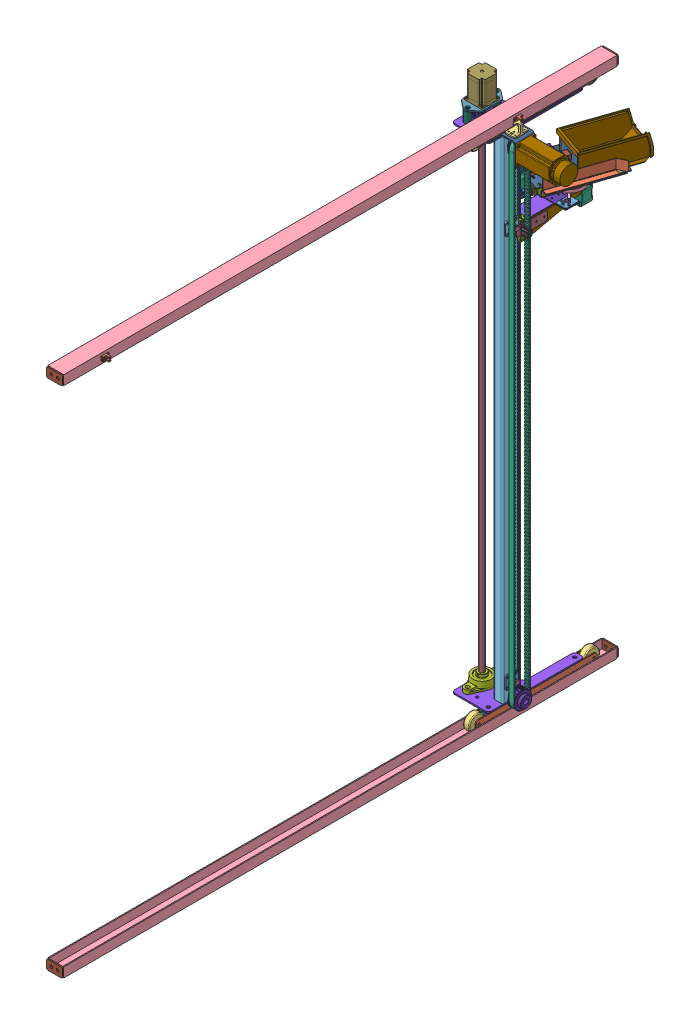
SolidWorks assembly T00001-000-R00, configuration Default. Lengths in mm.
Overall size (309.17 1703.5 1800.33).
110 component instances, 57 part files, 187 mates.
Components (placement in the parent):
- T00118-000-R00-1: T00118-000-R00 [Default] at (157.9488 226.0018 -468.4792) size (25 25 300)
- T00119-DXF-R00-1: T00119-DXF-R00 [Default] at (145.4488 226.0018 -318.4792) x (0 0 1) z (0 -1 0) size (380 3 25)
- T00119-DXF-R00-2: T00119-DXF-R00 [Default] at (173.4488 226.0018 -318.4792) x (0 0 -1) z (0 1 0) size (380 3 25)
- T00103-E00-R00-1: T00103-E00-R00 [Default] at (157.9488 226.0018 -138.4792) x (0 -0.996374 0.085085) z (0 0.085085 0.996374) size (50 22 50)
- T00103-E00-R00-2: T00103-E00-R00 [Default] at (157.9488 226.0018 -498.4792) x (0 -1 0) z (0 0 1) size (50 22 50)
- T00117-000-R00-1: T00117-000-R00 [Default] at (157.9488 198.0018 -560.9511) size (50 30 1732)
- T00112-000-R00-1: T00112-000-R00 [50 x 30 x 2.6x1700] at (142.9488 1012.5018 -263.4792) x (1 0 0) z (0 -1 0) size (30 50 1540)
- T00109-E00-R00-1: T00109-E00-R00 [HGR15R400CE20] at (157.9488 1772.5018 -263.4792) x (1 0 0) z (0 1 0) size (15 15 1530)
- T00100-E00-R00-4: T00100-E00-R00 [Default] at (82.9488 242.5018 -238.4792) x (0 1 0) z (0 0 1) size (65.14 65.88 113)
- T00120-DXF-R00-1: T00120-DXF-R00 [Default] at (100.4488 238.5018 -238.4792) x (0 0 -1) z (-1 0 0) size (300 4 115)
- T00120-DXF-R00-2: T00120-DXF-R00 [Default] at (100.4488 1782.5018 -238.4792) x (0 0 -1) z (-1 0 0) size (300 4 115)
- T00100-E00-R00-2: T00100-E00-R00 [Default] at (82.9488 1782.5018 -238.4792) x (0 -1 0) z (0 0 -1) size (65.14 65.88 113)
- T00160-E00-R00-8: T00160-E00-R00 [Default] at (216.9488 1755.5018 -238.4792) x (0 0 1) z (-1 0 0) size (60 69 159.8)
- T00121-0A4-R00-1: T00121-0A4-R00 [Default] at (216.9488 1751.5018 -238.4792) x (0 0 -1) z (0 -1 0) size (300 74 94)
- T00103-E00-R00-3: T00103-E00-R00 [Default] at (157.9488 1803.0018 -138.4792) x (0 -1 0) z (0 0 1) size (50 22 50)
- T00103-E00-R00-4: T00103-E00-R00 [Default] at (157.9488 1803.0018 -498.4792) x (0 0.952135 0.305677) z (0 0.305677 -0.952135) size (50 22 50)
- T00119-DXF-R00-3: T00119-DXF-R00 [Default] at (173.4488 1803.0018 -318.4792) x (0 0 1) z (0 -1 0) size (380 3 25)
- T00119-DXF-R00-4: T00119-DXF-R00 [Default] at (145.4488 1803.0018 -318.4792) x (0 0 -1) z (0 1 0) size (380 3 25)
- T00118-000-R00-2: T00118-000-R00 [Default] at (157.9488 1803.0018 -168.4792) x (1 0 0) z (0 0 -1) size (25 25 300)
- T00117-000-R00-2: T00117-000-R00 [Default] at (157.9488 1833.5018 -560.9511) x (-1 0 0) z (0 0 1) size (50 30 1732)
- T00122-DXF-R00-1: T00122-DXF-R00 [Default] at (157.9488 213.0018 1175.0489) size (50 30 4)
- T00122-DXF-R00-2: T00122-DXF-R00 [Default] at (157.9488 213.0018 -560.9511) size (50 30 4)
- T00122-DXF-R00-3: T00122-DXF-R00 [Default] at (157.9488 1818.5018 -564.9511) x (-1 0 0) z (0 0 -1) size (50 30 4)
- T00122-DXF-R00-4: T00122-DXF-R00 [Default] at (157.9488 1818.5018 1175.0489) size (50 30 4)
- T00106-E00-R00-6: T00106-E00-R00 [Default] at (84.9717 1862.7018 -130.0077) x (0 0 1) z (0 -1 0) size (56.4 57 96.6)
- T00123-000-R00-1: T00123-000-R00 [Default] at (82.9488 1823.9018 -238.4792) x (1 0 0) z (0 -1 0) size (15 15 1615)
- T00124-DXF-R00-1: T00124-DXF-R00 [Default] at (82.9488 1825.5018 -238.4792) x (0 0 1) z (-1 0 0) size (110 4 65)
- T00104-E00-R00-1: T00104-E00-R00 [Default] at (82.9488 1786.5018 -193.4792) x (0 1 0) z (0 0 1) size (35 20 20)
- T00104-E00-R00-2: T00104-E00-R00 [Default] at (82.9488 1786.5018 -283.4792) x (0 1 0) z (0 0 1) size (35 20 20)
- T00101-E00-R00-1: T00101-E00-R00 [Default] at (112.9488 1791.0018 -193.4792) size (22 7 22)
- T00101-E00-R00-2: T00101-E00-R00 [Default] at (112.9488 1791.0018 -283.4792) size (22 7 22)
- T00101-E00-R00-3: T00101-E00-R00 [Default] at (112.9488 1798.0018 -283.4792) x (-0.837169 0 -0.546944) z (-0.546944 0 0.837169) size (22 7 22)
- T00101-E00-R00-4: T00101-E00-R00 [Default] at (112.9488 1798.0018 -193.4792) x (-0.837169 0 -0.546944) z (-0.546944 0 0.837169) size (22 7 22)
- T00101-E00-R00-5: T00101-E00-R00 [Default] at (112.9488 234.0018 -283.4792) size (22 7 22)
- T00101-E00-R00-6: T00101-E00-R00 [Default] at (112.9488 227.0018 -283.4792) size (22 7 22)
- T00101-E00-R00-7: T00101-E00-R00 [Default] at (112.9488 234.0018 -193.4792) x (-0.837169 0 -0.546944) z (-0.546944 0 0.837169) size (22 7 22)
- T00101-E00-R00-8: T00101-E00-R00 [Default] at (112.9488 227.0018 -193.4792) x (-0.837169 0 -0.546944) z (-0.546944 0 0.837169) size (22 7 22)
- T00102-E00-R00-1: T00102-E00-R00 [Default] at (82.9488 237.5018 -238.4792) x (0 -1 0) z (-0.546944 0 0.837169) size (31 54 54)
- T00102-E00-R00-2: T00102-E00-R00 [Default] at (82.9488 1787.5018 -238.4792) x (0 1 0) z (0 0 1) size (31 54 54)
- T00102-E00-R00-3: T00102-E00-R00 [Default] at (210.9488 1755.5018 -238.4792) x (-1 0 0) z (0 -0.919553 -0.392965) size (31 54 54)
- T00125-0A4-R00-1: T00125-0A4-R00 [Default] at (137.9488 260.2518 -238.4792) x (0 0.966097 0.25818) z (0 0.25818 -0.966097) size (15 71.4 15)
- T00102-E00-R00-5: T00102-E00-R00 [Default] at (189.9488 260.2518 -238.4792) x (1 0 0) z (0 0.556413 0.830906) size (31 54 54)
- T00152-03D-R00-4: T00152-03D-R00 [Default] at (172.9488 297.5018 -238.6792) x (0 -1 0) z (0 0 1) size (40 4 40)
- T00149-E00-R00-2: T00149-E00-R00 [Default] at (195.8488 1815.5018 -247.7511) x (0 0 1) z (0 1 0) size (22.7 14.9 13.4)
- T00149-E00-R00-3: T00149-E00-R00 [Default] at (195.8488 1821.5018 1041.6323) x (0 0 -1) z (0 -1 0) size (22.7 14.9 13.4)
- T00150-03D-R00-3: T00150-03D-R00 [Default] at (191.1488 1790.5018 -238.4792) x (0 0 -1) z (1 0 0) size (45 29.75 32)
- T00153-E00-R00-1: T00153-E00-R00 [Default] at (180.9488 1523.996 -247.6792) x (0 -1 0) z (1 0 0) size (13 22.4 13.7)
- T00151-03D-R00-1: T00151-03D-R00 [Default] at (172.9488 1527.496 -238.4792) x (0 -1 0) z (0 0 1) size (40 4 40)
- T00153-E00-R00-2: T00153-E00-R00 [Default] at (180.9488 294.0018 -247.4815) x (0 -1 0) z (1 0 0) size (13 22.4 13.7)
- T00166-E00-R00-1: T00166-E00-R00 [Default] at (193.6988 1755.5018 107.1126) x (0 0 -1) z (1 0 0) size (52.05 1547.3 15)
- T00003-000-R02-2: T00003-000-R02 [Default] at (0 635.6909 -533.1535) size (206.44 185.95 380.78)
  - T00108-E00-R00-3: T00108-E00-R00 [Default] at (157.9488 862.2474 269.7743) x (1 0 0) z (0 1 0) size (34 23.7 61.49)
  - T00110-E00-R00-1: T00110-E00-R00 [HGR15R400CE20] at (220.7447 918.7474 -18.1171) x (-0.945846 0 -0.324616) z (0.324616 0 -0.945846) size (15 15 270)
  - T00108-E00-R00-4: T00108-E00-R00 [Default] at (154.4543 918.7474 175.0355) x (-0.945846 0 -0.324616) z (0.324616 0 -0.945846) size (34 23.7 61.49)
  - T00148-E00-R00-1: T00148-E00-R00 [Default] at (206.0289 941.2474 119.0644) x (-0.945846 0 -0.324616) z (0.324616 0 -0.945846) size (104.77 76.2 187.32)
  - T00006-000-R00-1: T00006-000-R00 [Default] at (104.8241 969.1581 159.4141) x (-0.945846 0 -0.324616) z (0 -1 0) size (100 103 92)
    - T00126-000-R02-1: T00126-000-R02 [Default] at (-76.7384 90.3354 70.4106) size (82 103 92)
    - T00005-000-R00-1: T00005-000-R00 [Default] at (-79.4687 62.4093 14.8739) x (0 -1 0) z (1 0 0) size (53.8 27.95 21.5)
      - T00154-E00-R01-1: T00154-E00-R01 [Default] at (15.674 22.2087 43.7303) size (53.8 16.25 21.5)
      - T00172-000-R01-1: T00172-000-R01 [Default] at (22.774 33.8087 43.7303) size (39 12 21.5)
      - T00171-000-R01-1: T00171-000-R01 [Default] at (15.674 10.2087 43.7303) size (53.2 12 21.5)
      - T00173-000-R01-1: T00173-000-R01 [Default] at (25.474 28.1587 43.0803) size (6 10 6)
      - socket head cap screw_iso-1: socket head cap screw_iso [ISO 4762 M2 x 16 - 16C] at (40.074 37.8087 51.9803) x (0 -1 0) z (0 0 1) size (18 3.8 3.8)
      - socket head cap screw_iso-4: socket head cap screw_iso [ISO 4762 M2 x 16 - 16C] at (5.074 37.8087 51.9803) x (0 -1 0) z (0 0 1) size (18 3.8 3.8)
      - socket head cap screw_iso-5: socket head cap screw_iso [ISO 4762 M2 x 16 - 16C] at (40.074 37.8087 35.4803) x (0 -1 0) z (0 0 1) size (18 3.8 3.8)
    - socket head cap screw_iso-1: socket head cap screw_iso [ISO 4762 M3 x 16 - 16C] at (-35.7384 58.3354 -6.3347) x (0 0 1) z (0 -1 0) size (19 5.5 5.5)
    - socket head cap screw_iso-2: socket head cap screw_iso [ISO 4762 M3 x 16 - 16C] at (-35.7384 35.3354 -6.3347) x (0 0 1) z (0 -1 0) size (19 5.5 5.5)
    - hex thin nut chamfered gradeab_iso-1: hex thin nut chamfered gradeab_iso [ISO - 4035 - M3 - C] at (-35.7384 35.3354 8.4653) size (5.5 6.35 1.8)
    - hex thin nut chamfered gradeab_iso-2: hex thin nut chamfered gradeab_iso [ISO - 4035 - M3 - C] at (-35.7384 58.3354 8.4653) size (5.5 6.35 1.8)
    - T00163-03D-R01-1: T00163-03D-R01 [Default] at (-4.7384 50.3354 4.6653) x (1 0 0) z (0 0 -1) size (38 30 18.2)
    - socket countersunk head screw_iso-1: socket countersunk head screw_iso [ISO 10642 - M3 x 8 - 8C] at (-9.7384 59.3354 1.6553) x (0 0 1) z (0.923728 0.383049 0) size (8 5.54 5.54)
    - socket countersunk head screw_iso-2: socket countersunk head screw_iso [ISO 10642 - M3 x 8 - 8C] at (-9.7384 41.3354 1.6553) x (0 0 1) z (0.923728 0.383049 0) size (8 5.54 5.54)
    - hex thin nut chamfered gradeab_iso-5: hex thin nut chamfered gradeab_iso [ISO - 4035 - M3 - C] at (-9.7384 41.3354 8.4653) size (5.5 6.35 1.8)
    - hex thin nut chamfered gradeab_iso-6: hex thin nut chamfered gradeab_iso [ISO - 4035 - M3 - C] at (-9.7384 59.3354 8.4653) size (5.5 6.35 1.8)
  - T00127-E00-R00-1: T00127-E00-R00 [DIN 625 - 6002 - 12,SI,NC,12_68] at (157.9488 901.2474 97.7743) x (0 1 0) z (0 0 1) size (9 32 32)
  - T00128-0A4-R00-1: T00128-0A4-R00 [Default] at (157.9488 887.7474 97.7743) x (1 0 0) z (0 -1 0) size (25 25 21)
  - T00129-E00-R00-1: T00129-E00-R00 [Circlip DIN 471 - 15 x 1.5] at (157.9488 905.9474 97.7743) x (0.837169 0 0.546944) z (0 -1 0) size (17.74 21.49 1.5)
  - T00130-0A4-R01-1: T00130-0A4-R01 [Default] at (157.9488 895.7474 97.7743) x (0.324616 0 -0.945846) z (0 -1 0) size (90 90 20)
  - T00132-E00-R00-4: T00132-E00-R00 [Metric - Spur gear 1M 60T 20PA 9FW ---S60N75H50L42N] at (157.9488 896.7474 97.7743) x (0 1 0) z (0 0 1) size (9 61.95 61.95)
  - T00107-E00-R00-1: T00107-E00-R00 [Varsayılan] at (157.9488 879.7474 61.7743) x (-1 0 0) z (0 1 0) size (42 58.5 65.65)
  - T00131-E00-R00-2: T00131-E00-R00 [Metric - Spur gear 1M 12T 20PA 8FW ---S12O10H14L5N] at (157.9488 896.7474 61.7743) x (0 1 0) z (0.924225 0 0.381849) size (14 13.61 13.61)
  - T00133-0A4-R00-3: T00133-0A4-R00 [Default] at (157.9488 862.2474 237.7743) x (1 0 0) z (0 1 0) size (49 210 57)
  - T00134-DXF-R00-1: T00134-DXF-R00 [Default] at (130.4488 892.7474 239.7743) x (0 0 -1) z (-1 0 0) size (155 44.25 3)
  - T00134-DXF-R00-2: T00134-DXF-R00 [Default] at (182.4488 892.7474 239.7743) x (0 0 -1) z (-1 0 0) size (155 44.25 3)
  - T00105-E00-R00-1: T00105-E00-R00 [Default] at (142.4488 890.7474 46.2743) x (1 0 0) z (0 -1 0) size (6 6 11)
  - T00105-E00-R00-2: T00105-E00-R00 [Default] at (173.4488 890.7474 46.2743) x (0.974973 0 -0.222324) z (0 -1 0) size (6 6 11)
  - T00105-E00-R00-3: T00105-E00-R00 [Default] at (142.4488 890.7474 77.2743) x (1 0 0) z (0 -1 0) size (6 6 11)
  - T00105-E00-R00-4: T00105-E00-R00 [Default] at (173.4488 890.7474 77.2743) x (1 0 0) z (0 -1 0) size (6 6 11)
  - T00107-E00-R00-2: T00107-E00-R00 [Varsayılan] at (104.3679 933.2474 184.5821) x (0.945846 0 0.324616) z (0.324616 0 -0.945846) size (42 58.5 65.65)
  - T00111-E00-R00-1: T00111-E00-R00 [Default] at (182.9251 933.2474 -44.3126) x (-0.536568 -0.823519 -0.184151) z (-0.778922 0.567289 -0.267328) size (10 240 10)
  - T00135-DXF-R01-1: T00135-DXF-R01 [Default] at (162.818 918.7474 83.5866) x (-0.324616 0 0.945846) z (-0.945846 0 -0.324616) size (219 39 131)
  - T00136-DXF-R01-1: T00136-DXF-R01 [Default] at (187.4488 877.7474 233.7743) x (0 0 -1) z (1 0 0) size (94.88 30 25)
  - T00138-000-R00-1: T00138-000-R00 [gespiegeld] at (139.5613 941.2474 -4.2179) x (0.324616 0 -0.945846) z (0.945846 0 0.324616) size (201.93 32 21.92)
  - T00153-E00-R00-4: T00153-E00-R00 [Default] at (89.0052 977.2474 133.8476) x (-0.324616 0 0.945846) z (0 1 0) size (13 22.4 13.7)
  - socket head cap screw_iso-1: socket head cap screw_iso [ISO 4762 M3 x 16 - 16N] at (76.144 978.7474 122.0328) x (0 -1 0) z (0.992143 0 0.125105) size (19 5.5 5.5)
  - hex nut style 1 gradeab_iso-1: hex nut style 1 gradeab_iso [ISO - 4032 - M3 - W - N] at (76.144 965.2474 122.0328) x (0.998096 0 0.061684) z (0 1 0) size (5.5 6.35 2.4)
  - socket head cap screw_iso-2: socket head cap screw_iso [ISO 4762 M3 x 16 - 16N] at (82.7649 978.7474 124.3052) x (0 -1 0) z (-0.061684 0 0.998096) size (19 5.5 5.5)
  - socket head cap screw_iso-3: socket head cap screw_iso [ISO 4762 M3 x 8 - 8N] at (86.5483 949.2474 125.6036) x (0.945846 0 0.324616) z (-0.316094 -0.227635 0.921014) size (11 5.5 5.5)
  - socket head cap screw_iso-4: socket head cap screw_iso [ISO 4762 M3 x 8 - 8N] at (86.5483 957.2474 125.6036) x (0.945846 0 0.324616) z (-0.159414 -0.871112 0.46449) size (11 5.5 5.5)
  - hex nut style 1 gradeab_iso-3: hex nut style 1 gradeab_iso [ISO - 4032 - M3 - W - N] at (82.7649 965.5626 124.3052) x (0.95019 0 0.311672) z (0 1 0) size (5.5 6.35 2.4)
  - hex nut style 1 gradeab_iso-4: hex nut style 1 gradeab_iso [ISO - 4032 - M3 - W - N] at (94.115 957.2474 128.2005) x (0.159414 0.871112 -0.46449) z (-0.945846 0 -0.324616) size (5.5 6.35 2.4)
  - hex nut style 1 gradeab_iso-5: hex nut style 1 gradeab_iso [ISO - 4032 - M3 - W - N] at (94.115 949.2474 128.2005) x (0.159414 0.871112 -0.46449) z (-0.945846 0 -0.324616) size (5.5 6.35 2.4)
  - T00153-E00-R00-7: T00153-E00-R00 [Default] at (120.7549 900.9974 134.9681) x (0.707107 0 0.707107) z (0 1 0) size (13 22.4 13.7)
  - T00153-E00-R00-8: T00153-E00-R00 [Default] at (195.1426 900.9974 134.9681) x (0.707107 0 -0.707107) z (0 1 0) size (13 22.4 13.7)
  - T00168-03D-R00-2: T00168-03D-R00 [Default] at (93.1692 959.2474 127.8759) x (-0.324616 0 0.945846) z (-0.945846 0 -0.324616) size (20 28 25.65)
  - T00161-0A4-R00-2: T00161-0A4-R00 [Default] at (157.9488 894.7474 147.7835) size (125 2 45)
  - T00164-03D-R00-1: T00164-03D-R00 [Default] at (157.9488 896.7474 147.7835) x (1 0 0) z (0 1 0) size (32 42.2 3)
  - T00165-03D-R00-1: T00165-03D-R00 [Default] at (250.9488 896.7474 147.7835) x (1 0 0) z (0 1 0) size (32 42.2 3)
  - T00137-000-R00-2: T00137-000-R00 [gespiegeld] at (236.0376 941.2474 28.893) x (0.324616 0 -0.945846) z (0.945846 0 0.324616) size (201.93 32 21.92)
  - T00162-03D-R03-1: T00162-03D-R03 [Default] at (174.1796 915.7474 50.482) x (-0.945846 0 -0.324616) z (0 -1 0) size (28 24.69 9)
Mates (geometry in assembly coordinates):
- Coincident1: coincident: plane of T00118-000-R00-1 through (170.4488 216.5018 -168.4792) normal (1 0 0); plane of T00119-DXF-R00-2 through (170.4488 228.5018 -498.4792) normal (-1 0 0)
- Coincident2: coincident: plane of T00118-000-R00-1 through (148.4488 238.5018 -168.4792) normal (0 1 0); plane of T00119-DXF-R00-2 through (170.4488 238.5018 -138.4792) normal (0 1 0)
- Coincident3: coincident: plane of T00118-000-R00-1 through (145.4488 216.5018 -168.4792) normal (-1 0 0); plane of T00119-DXF-R00-1 through (145.4488 223.5018 -138.4792) normal (1 0 0)
- Coincident4: coincident: plane of T00118-000-R00-1 through (148.4488 213.5018 -168.4792) normal (0 -1 0); plane of T00119-DXF-R00-1 through (142.4488 213.5018 -498.4792) normal (0 -1 0)
- Coincident5: coincident: plane of T00119-DXF-R00-1 through (142.4488 228.5018 -128.4792) normal (0 0 1); plane of T00119-DXF-R00-2 through (170.4488 223.5018 -128.4792) normal (0 0 1)
- Width1: width: plane of T00119-DXF-R00-1 through (142.4488 228.5018 -128.4792) normal (0 0 1); plane of T00119-DXF-R00-1 through (142.4488 228.5018 -508.4792) normal (0 0 -1); plane of T00118-000-R00-1 through (148.4488 216.5018 -468.4792) normal (0 0 -1); plane of T00118-000-R00-1 through (148.4488 216.5018 -168.4792) normal (0 0 1)
- Concentric1: concentric: cylinder of T00119-DXF-R00-1 through (142.4488 226.0018 -138.4792) axis (1 0 0) radius 3.25; cylinder of T00103-E00-R00-1 through (157.9488 226.0018 -138.4792) axis (-1 0 0) radius 3
- Concentric2: concentric: cylinder of T00119-DXF-R00-1 through (142.4488 226.0018 -498.4792) axis (1 0 0) radius 3.25; cylinder of T00103-E00-R00-2 through (157.9488 226.0018 -498.4792) axis (-1 0 0) radius 3
- Width2: width: plane of T00103-E00-R00-2 through (168.9488 223.0018 -498.4792) normal (1 0 0); plane of T00103-E00-R00-2 through (146.9488 219.0018 -498.4792) normal (-1 0 0); plane of T00119-DXF-R00-1 through (145.4488 223.5018 -138.4792) normal (1 0 0); plane of T00119-DXF-R00-2 through (170.4488 228.5018 -498.4792) normal (-1 0 0)
- Width3: width: plane of T00103-E00-R00-1 through (168.9488 223.0127 -138.2239) normal (1 0 0); plane of T00103-E00-R00-1 through (146.9488 219.0272 -137.8836) normal (-1 0 0); plane of T00119-DXF-R00-1 through (142.4488 223.5018 -138.4792) normal (-1 0 0); plane of T00119-DXF-R00-2 through (173.4488 228.5018 -498.4792) normal (1 0 0)
- Tangent1: tangent: cylinder of T00103-E00-R00-1 through (157.9488 226.0018 -138.4792) axis (-1 0 0) radius 25; plane of T00117-000-R00-1 through (135.9488 201.0018 1171.0489) normal (0 1 0)
- Tangent2: tangent: cylinder of T00103-E00-R00-2 through (157.9488 226.0018 -498.4792) axis (-1 0 0) radius 25; plane of T00117-000-R00-1 through (135.9488 201.0018 1171.0489) normal (0 1 0)
- Width4: width: plane of T00119-DXF-R00-2 through (173.4488 228.5018 -498.4792) normal (1 0 0); plane of T00119-DXF-R00-1 through (142.4488 223.5018 -138.4792) normal (-1 0 0); plane of T00117-000-R00-1 through (179.9488 201.0018 1171.0489) normal (-1 0 0); plane of T00117-000-R00-1 through (135.9488 201.0018 1171.0489) normal (1 0 0)
- Width9: width: plane of T00112-000-R00-1 through (172.9488 242.5018 -218.6792) normal (1 0 0); plane of T00112-000-R00-1 through (142.9488 242.5018 -258.2792) normal (-1 0 0); plane of T00119-DXF-R00-1 through (142.4488 223.5018 -138.4792) normal (-1 0 0); plane of T00119-DXF-R00-2 through (173.4488 228.5018 -498.4792) normal (1 0 0)
- Coincident16: coincident: plane of T00112-000-R00-1 through (148.1488 242.5018 -263.4792) normal (0 0 -1); plane of T00109-E00-R00-1 through (150.9488 242.5018 -263.4792) normal (0 0 1)
- Width10: width: plane of T00003-000-R02-2/T00108-E00-R00-3 through (162.6988 1527.1383 -269.7949) normal (-1 0 0); plane of T00003-000-R02-2/T00108-E00-R00-3 through (153.1988 1527.1383 -269.7949) normal (1 0 0); plane of T00109-E00-R00-1 through (150.4488 242.5018 -275.1449) normal (-1 0 0); plane of T00109-E00-R00-1 through (165.4488 242.5018 -275.1449) normal (1 0 0)
- Coincident18: coincident: plane of T00003-000-R02-2/T00108-E00-R00-3 through (162.9902 1517.6383 -278.4792) normal (0 0 1); plane of T00109-E00-R00-1 through (162.9488 242.5018 -278.4792) normal (0 0 -1)
- Width11: width: plane of T00112-000-R00-1 through (172.9488 242.5018 -218.6792) normal (1 0 0); plane of T00112-000-R00-1 through (142.9488 242.5018 -258.2792) normal (-1 0 0); plane of T00109-E00-R00-1 through (150.4488 242.5018 -263.9792) normal (-1 0 0); plane of T00109-E00-R00-1 through (165.4488 242.5018 -263.9792) normal (1 0 0)
- Coincident62: coincident: plane of T00118-000-R00-1 through (148.4488 238.5018 -168.4792) normal (0 1 0); plane of T00120-DXF-R00-1 through (100.4488 238.5018 -238.4792) normal (0 -1 0)
- Width15: width: plane of T00120-DXF-R00-1 through (142.9488 242.5018 -308.4792) normal (-1 0 0); plane of T00120-DXF-R00-1 through (172.9488 242.5018 -168.4792) normal (1 0 0); plane of T00119-DXF-R00-1 through (142.4488 223.5018 -138.4792) normal (-1 0 0); plane of T00119-DXF-R00-2 through (173.4488 228.5018 -498.4792) normal (1 0 0)
- Coincident63: coincident: plane of T00118-000-R00-1 through (148.4488 216.5018 -168.4792) normal (0 0 1); plane of T00120-DXF-R00-1 through (57.9488 242.5018 -168.4792) normal (0 0 1)
- Width16: width: plane of T00120-DXF-R00-1 through (57.9488 242.5018 -168.4792) normal (0 0 1); plane of T00120-DXF-R00-1 through (57.9488 242.5018 -308.4792) normal (0 0 -1); plane of T00112-000-R00-1 through (148.1488 242.5018 -263.4792) normal (0 0 -1); plane of T00112-000-R00-1 through (167.7488 242.5018 -213.4792) normal (0 0 1)
- Coincident64: coincident: plane of T00109-E00-R00-1 through (164.4488 242.5018 -266.565) normal (0 -1 0); plane of T00120-DXF-R00-1 through (100.4488 242.5018 -238.4792) normal (0 1 0)
- Coincident65: coincident: plane of T00112-000-R00-1 through (167.7488 242.5018 -218.6792) normal (0 -1 0); plane of T00120-DXF-R00-1 through (100.4488 242.5018 -238.4792) normal (0 1 0)
- Coincident70: coincident: plane of T00100-E00-R00-4 through (82.9488 242.5018 -238.4792) normal (0 -1 0); plane of T00120-DXF-R00-1 through (100.4488 242.5018 -238.4792) normal (0 1 0)
- Concentric28: concentric: cylinder of T00120-DXF-R00-1 through (82.9488 242.5018 -193.4792) axis (0 -1 0) radius 6.25; cylinder of T00100-E00-R00-4 through (82.9488 248.5018 -193.4792) axis (0 1 0) radius 6
- Concentric29: concentric: cylinder of T00120-DXF-R00-1 through (82.9488 242.5018 -283.4792) axis (0 -1 0) radius 6.25; circle of T00100-E00-R00-4
- Coincident78: coincident: plane of T00112-000-R00-1 through (167.7488 1782.5018 -218.6792) normal (0 1 0); plane of T00120-DXF-R00-2 through (100.4488 1782.5018 -238.4792) normal (0 -1 0)
- Coincident79: coincident: plane of T00120-DXF-R00-1 through (57.9488 242.5018 -168.4792) normal (0 0 1); plane of T00120-DXF-R00-2 through (57.9488 1786.5018 -168.4792) normal (0 0 1)
- Coincident80: coincident: plane of T00120-DXF-R00-1 through (57.9488 242.5018 -308.4792) normal (-1 0 0); plane of T00120-DXF-R00-2 through (57.9488 1786.5018 -308.4792) normal (-1 0 0)
- Coincident81: coincident: plane of T00120-DXF-R00-2 through (100.4488 1782.5018 -28.555) normal (0 -1 0); plane of ? through (82.9488 1782.5018 -28.555) normal (0 1 0)
- Concentric32: concentric: cylinder of T00120-DXF-R00-2 through (82.9488 1786.5018 -73.555) axis (0 -1 0) radius 6.25; cylinder of ? through (82.9488 1776.5018 -73.555) axis (0 -1 0) radius 6
- Concentric33: concentric: cylinder of T00120-DXF-R00-2 through (82.9488 1786.5018 16.445) axis (0 -1 0) radius 6.25; cylinder of ? through (82.9488 1776.5018 16.445) axis (0 -1 0) radius 6
- Coincident86: coincident: plane of T00120-DXF-R00-2 through (100.4488 1786.5018 -238.4792) normal (0 1 0); plane of T00121-0A4-R00-1 through (216.9488 1786.5018 -238.4792) normal (0 -1 0)
- Concentric37: concentric: cylinder of T00120-DXF-R00-2 through (157.9488 1786.5018 -183.4792) axis (0 -1 0) radius 5.25; cylinder of T00121-0A4-R00-1 through (157.9488 1786.5018 -183.4792) axis (0 1 0) radius 5.25
- Concentric38: concentric: cylinder of T00120-DXF-R00-2 through (157.9488 1786.5018 -453.4792) axis (0 -1 0) radius 5.25; cylinder of T00121-0A4-R00-1 through (157.9488 1786.5018 -453.4792) axis (0 1 0) radius 5.25
- Coincident87: coincident: plane of T00160-E00-R00-8 through (216.9488 1728.5018 -265.4792) normal (-1 0 0); plane of T00121-0A4-R00-1 through (216.9488 1711.5018 -255.9792) normal (1 0 0)
- LimitDistance3: limit distance = 1299.5281 mm: plane of T00119-DXF-R00-2 through (170.4488 223.5018 -128.4792) normal (0 0 1); plane of T00117-000-R00-1 through (157.9488 198.0018 1171.0489) normal (0 0 1)
- Coincident93: coincident: plane of T00119-DXF-R00-3 through (170.4488 1790.5018 -498.4792) normal (0 -1 0); plane of T00118-000-R00-2 through (148.4488 1790.5018 -468.4792) normal (0 -1 0)
- Coincident94: coincident: plane of T00119-DXF-R00-3 through (170.4488 1805.5018 -508.4792) normal (0 0 -1); plane of T00119-DXF-R00-4 through (142.4488 1800.5018 -508.4792) normal (0 0 -1)
- Coincident95: coincident: plane of T00119-DXF-R00-3 through (170.4488 1800.5018 -138.4792) normal (-1 0 0); plane of T00118-000-R00-2 through (170.4488 1812.5018 -468.4792) normal (1 0 0)
- Coincident96: coincident: plane of T00119-DXF-R00-4 through (142.4488 1815.5018 -138.4792) normal (0 1 0); plane of T00118-000-R00-2 through (148.4488 1815.5018 -468.4792) normal (0 1 0)
- Coincident97: coincident: plane of T00119-DXF-R00-4 through (145.4488 1805.5018 -498.4792) normal (1 0 0); plane of T00118-000-R00-2 through (145.4488 1812.5018 -468.4792) normal (-1 0 0)
- Width17: width: plane of T00119-DXF-R00-4 through (142.4488 1800.5018 -508.4792) normal (0 0 -1); plane of T00119-DXF-R00-4 through (142.4488 1800.5018 -128.4792) normal (0 0 1); plane of T00118-000-R00-2 through (148.4488 1812.5018 -168.4792) normal (0 0 1); plane of T00118-000-R00-2 through (148.4488 1812.5018 -468.4792) normal (0 0 -1)
- Width18: width: plane of T00103-E00-R00-4 through (168.9488 1805.8582 -497.5622) normal (1 0 0); plane of T00103-E00-R00-4 through (146.9488 1809.6667 -496.3395) normal (-1 0 0); plane of T00119-DXF-R00-4 through (142.4488 1805.5018 -498.4792) normal (-1 0 0); plane of T00119-DXF-R00-3 through (173.4488 1800.5018 -138.4792) normal (1 0 0)
- Concentric43: concentric: cylinder of T00103-E00-R00-3 through (157.9488 1803.0018 -138.4792) axis (-1 0 0) radius 3; cylinder of T00119-DXF-R00-4 through (142.4488 1803.0018 -138.4792) axis (1 0 0) radius 3.25
- Concentric44: concentric: cylinder of T00103-E00-R00-4 through (157.9488 1803.0018 -498.4792) axis (-1 0 0) radius 3; cylinder of T00119-DXF-R00-4 through (142.4488 1803.0018 -498.4792) axis (1 0 0) radius 3.25
- Width19: width: plane of T00103-E00-R00-3 through (168.9488 1800.0018 -138.4792) normal (1 0 0); plane of T00103-E00-R00-3 through (146.9488 1796.0018 -138.4792) normal (-1 0 0); plane of T00119-DXF-R00-4 through (145.4488 1805.5018 -498.4792) normal (1 0 0); plane of T00119-DXF-R00-3 through (170.4488 1800.5018 -138.4792) normal (-1 0 0)
- Coincident98: coincident: plane of T00121-0A4-R00-1 through (216.9488 1790.5018 -238.4792) normal (0 1 0); plane of T00118-000-R00-2 through (148.4488 1790.5018 -468.4792) normal (0 -1 0)
- Width20: width: plane of T00119-DXF-R00-3 through (173.4488 1800.5018 -138.4792) normal (1 0 0); plane of T00119-DXF-R00-4 through (142.4488 1805.5018 -498.4792) normal (-1 0 0); plane of T00121-0A4-R00-1 through (172.9488 1786.5018 -268.4792) normal (1 0 0); plane of T00121-0A4-R00-1 through (142.9488 1786.5018 -168.4792) normal (-1 0 0)
- Coincident99: coincident: plane of T00121-0A4-R00-1 through (172.9488 1786.5018 -168.4792) normal (0 0 1); plane of T00118-000-R00-2 through (148.4488 1812.5018 -168.4792) normal (0 0 1)
- Coincident100: coincident: plane of T00117-000-R00-1 through (132.9488 198.0018 1171.0489) normal (-1 0 0); plane of T00117-000-R00-2 through (132.9488 1833.5018 1171.0489) normal (-1 0 0)
- Coincident101: coincident: plane of T00117-000-R00-1 through (157.9488 198.0018 -560.9511) normal (0 0 -1); plane of T00117-000-R00-2 through (157.9488 1833.5018 -560.9511) normal (0 0 -1)
- Distance24: distance = 15 mm: plane of T00118-000-R00-2 through (148.4488 1815.5018 -468.4792) normal (0 1 0); plane of T00117-000-R00-2 through (179.9488 1830.5018 1171.0489) normal (0 -1 0)
- Coincident103: coincident: plane of T00117-000-R00-1 through (132.9488 198.0018 1171.0489) normal (-1 0 0); plane of T00122-DXF-R00-1 through (132.9488 203.0018 1171.0489) normal (-1 0 0)
- Coincident104: coincident: plane of T00117-000-R00-1 through (157.9488 198.0018 1171.0489) normal (0 0 1); plane of T00122-DXF-R00-1 through (137.9488 203.0018 1171.0489) normal (0 0 -1)
- Coincident105: coincident: plane of T00117-000-R00-1 through (132.9488 198.0018 1171.0489) normal (0 -1 0); plane of T00122-DXF-R00-1 through (137.9488 198.0018 1171.0489) normal (0 -1 0)
- Coincident106: coincident: plane of T00117-000-R00-1 through (132.9488 198.0018 1171.0489) normal (-1 0 0); plane of T00122-DXF-R00-2 through (132.9488 203.0018 -564.9511) normal (-1 0 0)
- Coincident107: coincident: plane of T00117-000-R00-1 through (157.9488 198.0018 -560.9511) normal (0 0 -1); plane of T00122-DXF-R00-2 through (137.9488 203.0018 -560.9511) normal (0 0 1)
- Coincident108: coincident: plane of T00117-000-R00-1 through (132.9488 198.0018 1171.0489) normal (0 -1 0); plane of T00122-DXF-R00-2 through (137.9488 198.0018 -564.9511) normal (0 -1 0)
- Coincident109: coincident: plane of T00117-000-R00-2 through (157.9488 1833.5018 -560.9511) normal (0 0 -1); plane of T00122-DXF-R00-3 through (177.9488 1808.5018 -560.9511) normal (0 0 1)
- Coincident110: coincident: plane of T00117-000-R00-2 through (182.9488 1833.5018 1171.0489) normal (0 1 0); plane of T00122-DXF-R00-3 through (177.9488 1833.5018 -560.9511) normal (0 1 0)
- Coincident111: coincident: plane of T00117-000-R00-2 through (132.9488 1833.5018 1171.0489) normal (-1 0 0); plane of T00122-DXF-R00-3 through (132.9488 1808.5018 -560.9511) normal (-1 0 0)
- Coincident112: coincident: plane of T00117-000-R00-2 through (157.9488 1833.5018 1171.0489) normal (0 0 1); plane of T00122-DXF-R00-4 through (137.9488 1808.5018 1171.0489) normal (0 0 -1)
- Coincident113: coincident: plane of T00117-000-R00-2 through (132.9488 1833.5018 1171.0489) normal (-1 0 0); plane of T00122-DXF-R00-4 through (132.9488 1808.5018 1171.0489) normal (-1 0 0)
- Coincident114: coincident: plane of T00117-000-R00-2 through (182.9488 1833.5018 1171.0489) normal (0 1 0); plane of T00122-DXF-R00-4 through (137.9488 1833.5018 1171.0489) normal (0 1 0)
- Slot1: slot: cylinder of T00160-E00-R00-8 through (221.7488 1779.0718 -214.9092) axis (-1 0 0) radius 2.5; plane of T00121-0A4-R00-1 through (212.9488 1771.0718 -217.6592) normal (0 0 1); cylinder of T00121-0A4-R00-1 through (212.9488 1779.0718 -214.9092) axis (1 0 0) radius 2.75
- Slot2: slot: cylinder of T00160-E00-R00-8 through (221.7488 1731.9318 -214.9092) axis (-1 0 0) radius 2.5; cylinder of T00121-0A4-R00-1 through (212.9488 1723.9318 -214.9092) axis (1 0 0) radius 2.75; cylinder of T00121-0A4-R00-1 through (212.9488 1731.9318 -214.9092) axis (1 0 0) radius 2.75
- Concentric45: concentric: cylinder of T00120-DXF-R00-2 through (82.9488 1786.5018 129.3032) axis (0 -1 0) radius 10; cylinder of ? through (82.9488 1804.9018 129.3032) axis (0 1 0) radius 4
- Parallel1: parallel: plane of T00120-DXF-R00-2 through (57.9488 1786.5018 59.3032) normal (-1 0 0); plane of ? through (54.7488 1825.5018 104.1032) normal (-1 0 0)
- Coincident115: coincident: plane of ? through (82.9488 1823.9018 129.3032) normal (0 -1 0); plane of T00123-000-R00-1 through (82.9488 1823.9018 129.3032) normal (0 1 0)
- Concentric46: concentric: cylinder of ? through (82.9488 1804.9018 129.3032) axis (0 1 0) radius 4; cylinder of T00123-000-R00-1 through (82.9488 1783.9018 129.3032) axis (0 1 0) radius 4
- Coincident116: coincident: plane of ? through (108.1488 1825.5018 104.1032) normal (0 -1 0); plane of T00124-DXF-R00-1 through (82.9488 1825.5018 174.3032) normal (0 1 0)
- Concentric47: concentric: cylinder of T00123-000-R00-1 through (82.9488 208.9018 -238.4792) axis (0 1 0) radius 7.5; cylinder of T00124-DXF-R00-1 through (82.9488 1821.5018 -238.4792) axis (0 1 0) radius 20
- Concentric48: concentric: cylinder of T00120-DXF-R00-2 through (82.9488 1786.5018 -283.4792) axis (0 -1 0) radius 6.25; cylinder of T00124-DXF-R00-1 through (82.9488 1821.5018 -283.4792) axis (0 1 0) radius 6.25
- Coincident117: coincident: plane of T00120-DXF-R00-2 through (100.4488 1786.5018 -238.4792) normal (0 1 0); plane of T00104-E00-R00-2 through (76.9488 1786.5018 -283.4792) normal (0 -1 0)
- Concentric49: concentric: cylinder of T00120-DXF-R00-2 through (82.9488 1786.5018 -283.4792) axis (0 -1 0) radius 6.25; cylinder of T00104-E00-R00-2 through (82.9488 786.5018 -283.4792) axis (0 -1 0) radius 10
- Coincident118: coincident: plane of T00124-DXF-R00-1 through (82.9488 1821.5018 -193.4792) normal (0 -1 0); plane of T00104-E00-R00-2 through (76.9488 1821.5018 -283.4792) normal (0 1 0)
- Coincident119: coincident: plane of T00120-DXF-R00-2 through (100.4488 1786.5018 -238.4792) normal (0 1 0); plane of T00104-E00-R00-1 through (76.9488 1786.5018 -193.4792) normal (0 -1 0)
- Concentric50: concentric: cylinder of T00120-DXF-R00-2 through (82.9488 1786.5018 -193.4792) axis (0 -1 0) radius 6.25; cylinder of T00104-E00-R00-1 through (82.9488 786.5018 -193.4792) axis (0 -1 0) radius 10
- Concentric51: concentric: cylinder of T00120-DXF-R00-2 through (112.9488 1786.5018 -193.4792) axis (0 -1 0) radius 4.25; cylinder of T00101-E00-R00-1 through (112.9488 1791.0018 -193.4792) axis (0 1 0) radius 4
- Concentric52: concentric: cylinder of T00120-DXF-R00-2 through (112.9488 1786.5018 -283.4792) axis (0 -1 0) radius 4.25; cylinder of T00101-E00-R00-2 through (112.9488 1791.0018 -283.4792) axis (0 1 0) radius 4
- Distance25: distance = 1 mm: plane of T00101-E00-R00-2 through (117.9488 1787.5018 -283.4792) normal (0 -1 0); plane of T00120-DXF-R00-2 through (100.4488 1786.5018 -238.4792) normal (0 1 0)
- Coincident121: coincident: plane of T00101-E00-R00-1 through (117.9488 1794.5018 -193.4792) normal (0 1 0); plane of T00101-E00-R00-2 through (117.9488 1794.5018 -283.4792) normal (0 1 0)
- Coincident122: coincident: plane of T00101-E00-R00-2 through (117.9488 1794.5018 -283.4792) normal (0 1 0); plane of T00101-E00-R00-3 through (108.7629 1794.5018 -286.2139) normal (0 -1 0)
- Concentric53: concentric: cylinder of T00101-E00-R00-2 through (112.9488 1791.0018 -283.4792) axis (0 1 0) radius 11; cylinder of T00101-E00-R00-3 through (112.9488 1798.0018 -283.4792) axis (0 -1 0) radius 11
- Coincident123: coincident: plane of T00101-E00-R00-1 through (117.9488 1794.5018 -193.4792) normal (0 1 0); plane of T00101-E00-R00-4 through (108.7629 1794.5018 -196.2139) normal (0 -1 0)
- Concentric54: concentric: cylinder of T00101-E00-R00-1 through (112.9488 1791.0018 -193.4792) axis (0 1 0) radius 11; cylinder of T00101-E00-R00-4 through (112.9488 1798.0018 -193.4792) axis (0 -1 0) radius 11
- Distance26: distance = 1 mm: plane of T00101-E00-R00-5 through (117.9488 237.5018 -283.4792) normal (0 1 0); plane of T00120-DXF-R00-1 through (100.4488 238.5018 -238.4792) normal (0 -1 0)
- Concentric55: concentric: circle of T00120-DXF-R00-1; cylinder of T00101-E00-R00-5 through (112.9488 234.0018 -283.4792) axis (0 1 0) radius 11
- Coincident125: coincident: plane of T00101-E00-R00-5 through (123.9488 230.5018 -283.4792) normal (0 -1 0); plane of T00101-E00-R00-6 through (117.9488 230.5018 -283.4792) normal (0 1 0)
- Concentric56: concentric: cylinder of T00101-E00-R00-5 through (112.9488 234.0018 -283.4792) axis (0 1 0) radius 11; cylinder of T00101-E00-R00-6 through (112.9488 227.0018 -283.4792) axis (0 1 0) radius 11
- Distance27: distance = 1 mm: plane of T00101-E00-R00-7 through (108.7629 237.5018 -196.2139) normal (0 1 0); plane of T00120-DXF-R00-1 through (100.4488 238.5018 -238.4792) normal (0 -1 0)
- Concentric57: concentric: cylinder of T00120-DXF-R00-1 through (112.9488 242.5018 -193.4792) axis (0 -1 0) radius 4.25; cylinder of T00101-E00-R00-7 through (112.9488 234.0018 -193.4792) axis (0 -1 0) radius 11
- Coincident127: coincident: plane of T00101-E00-R00-7 through (108.7629 230.5018 -196.2139) normal (0 -1 0); plane of T00101-E00-R00-8 through (103.7399 230.5018 -199.4956) normal (0 1 0)
- Concentric58: concentric: cylinder of T00101-E00-R00-7 through (112.9488 234.0018 -193.4792) axis (0 -1 0) radius 11; cylinder of T00101-E00-R00-8 through (112.9488 227.0018 -193.4792) axis (0 -1 0) radius 11
- Concentric59: concentric: cylinder of T00123-000-R00-1 through (82.9488 208.9018 -238.4792) axis (0 1 0) radius 7.5; cylinder of T00102-E00-R00-1 through (82.9488 1416.5905 -238.4792) axis (0 1 0) radius 7.5
- Distance28: distance = 1 mm: plane of T00102-E00-R00-1 through (105.5523 237.5018 -223.7117) normal (0 1 0); plane of T00120-DXF-R00-1 through (100.4488 238.5018 -238.4792) normal (0 -1 0)
- Distance29: distance = 1 mm: plane of T00102-E00-R00-2 through (55.9488 1787.5018 -238.4792) normal (0 -1 0); plane of T00120-DXF-R00-2 through (100.4488 1786.5018 -238.4792) normal (0 1 0)
- Concentric60: concentric: cylinder of T00123-000-R00-1 through (82.9488 208.9018 -238.4792) axis (0 1 0) radius 7.5; cylinder of T00102-E00-R00-2 through (82.9488 608.4131 -238.4792) axis (0 -1 0) radius 17.5
- Concentric61: concentric: cylinder of ? through (196.3488 1750.7712 129.3032) axis (1 0 0) radius 4; cylinder of T00102-E00-R00-3 through (1389.0375 1755.5018 -204.8848) axis (1 0 0) radius 17.5
- Distance32: distance = 6 mm: plane of T00102-E00-R00-3 through (210.9488 1766.1118 -263.3071) normal (1 0 0); plane of T00160-E00-R00-8 through (216.9488 1728.5018 -265.4792) normal (-1 0 0)
- Coincident135: coincident: plane of T00112-000-R00-1 through (172.9488 242.5018 -218.6792) normal (1 0 0); plane of T00125-0A4-R00-1 through (172.9488 266.0484 -236.9301) normal (-1 0 0)
- Concentric68: concentric: cylinder of T00125-0A4-R00-1 through (209.3488 260.2518 -238.4792) axis (1 0 0) radius 6; cylinder of T00102-E00-R00-5 through (-989.14 260.2518 -238.4792) axis (-1 0 0) radius 7.5
- Distance33: distance = 17 mm: plane of T00102-E00-R00-5 through (189.9488 282.6862 -253.5023) normal (-1 0 0); plane of T00112-000-R00-1 through (172.9488 242.5018 -218.6792) normal (1 0 0)
- Lock1: lock: unknown of T00112-000-R00-1; unknown of T00125-0A4-R00-1
- Coincident137: coincident: plane of T00120-DXF-R00-2 through (100.4488 1782.5018 -238.4792) normal (0 -1 0); plane of T00100-E00-R00-2 through (82.9488 1782.5018 -238.4792) normal (0 1 0)
- Concentric69: concentric: cylinder of T00120-DXF-R00-2 through (82.9488 1786.5018 -193.4792) axis (0 -1 0) radius 6.25; cylinder of T00100-E00-R00-2 through (82.9488 1776.5018 -193.4792) axis (0 -1 0) radius 6
- Concentric70: concentric: cylinder of T00100-E00-R00-2 through (82.9488 1776.5018 -283.4792) axis (0 -1 0) radius 6; cylinder of T00104-E00-R00-2 through (82.9488 786.5018 -283.4792) axis (0 -1 0) radius 6
- Coincident140: coincident: plane of T00121-0A4-R00-1 through (216.9488 1790.5018 -238.9511) normal (0 1 0); plane of ? through (199.1064 1790.5018 -261.4511) normal (0 -1 0)
- Coincident141: coincident: plane of T00160-E00-R00-8 through (216.9488 1728.5018 -265.4792) normal (-1 0 0); plane of T00121-0A4-R00-1 through (216.9488 1711.5018 -255.9792) normal (1 0 0)
- Concentric72: concentric: circle of T00121-0A4-R00-1; cylinder of T00160-E00-R00-8 through (221.7488 1779.0718 -262.0492) axis (-1 0 0) radius 2.5
- Concentric75: concentric: cylinder of T00121-0A4-R00-1 through (212.9488 1731.9318 -214.9092) axis (1 0 0) radius 2.75; cylinder of T00160-E00-R00-8 through (221.7488 1731.9318 -214.9092) axis (-1 0 0) radius 2.5
- Concentric76: concentric: cylinder of T00102-E00-R00-3 through (1390.0375 1755.5018 -238.4792) axis (1 0 0) radius 7.5; cylinder of T00160-E00-R00-8 through (194.9488 1755.5018 -238.4792) axis (1 0 0) radius 4
- Concentric77: concentric: cylinder of T00106-E00-R00-6 through (59.3788 1825.5018 -262.0492) axis (0 1 0) radius 2.5; circle of T00124-DXF-R00-1
- Concentric79: concentric: cylinder of T00106-E00-R00-6 through (106.5188 1825.5018 -214.9092) axis (0 1 0) radius 2.5; cylinder of T00124-DXF-R00-1 through (106.5188 1821.5018 -214.9092) axis (0 1 0) radius 2.75
- Coincident144: coincident: plane of T00106-E00-R00-6 through (108.1488 1825.5018 -263.6792) normal (0 -1 0); plane of T00124-DXF-R00-1 through (82.9488 1825.5018 -193.4792) normal (0 1 0)
- Coincident149: coincident: plane of ? through (192.1038 1793.5018 -146.0303) normal (0 1 0); plane of ? through (204.6488 1793.5018 -223.0303) normal (0 -1 0)
- Parallel2: parallel: plane of T00121-0A4-R00-1 through (208.9488 1782.5018 -208.9511) normal (0 0 1); plane of ? through (191.2488 1799.5018 -226.7511) normal (0 0 1)
- Width24: width: plane of T00121-0A4-R00-1 through (208.9488 1782.5018 -208.9511) normal (0 0 1); plane of T00121-0A4-R00-1 through (208.9488 1782.5018 -268.9511) normal (0 0 -1); plane of ? through (194.9488 1808.4018 -235.9511) normal (0 0 1); plane of ? through (194.9488 1808.4018 -241.9511) normal (0 0 -1)
- Distance38: distance = 15 mm: plane of ? through (197.9488 1806.4018 -238.9511) normal (-1 0 0); plane of T00117-000-R00-2 through (182.9488 1833.5018 1171.0489) normal (1 0 0)
- Coincident150: coincident: line of T00117-000-R00-2 through (182.9488 1803.5018 1171.0489) axis (0 0 -1); plane of ? through (186.9488 1803.5018 -270.9511) normal (0 -1 0)
- Coincident151: coincident: plane of T00117-000-R00-2 through (182.9488 1833.5018 1171.0489) normal (1 0 0); plane of ? through (182.9488 1818.5018 -240.9511) normal (-1 0 0)
- Coincident154: coincident: plane of T00121-0A4-R00-1 through (216.9488 1790.5018 -226.0303) normal (0 1 0); plane of ? through (192.1038 1790.5018 -146.0303) normal (0 -1 0)
- InPlace1: in place: plane of ? through (204.6488 1809.8695 -221.058) normal (0 -1 0); plane of ? through (0 1809.8695 0) normal (0 -1 0); moOrthogonalPlaneRef_w of ? through (204.6488 1809.8695 -221.058) normal (0 -1 0); plane of ? through (0 1809.8695 0) normal (0 0 -1); plane of ? through (204.6488 1809.8695 -221.058) normal (0 -1 0); plane of ? through (0 1809.8695 0) normal (-1 0 0); plane of ? through (204.6488 1793.5018 -235.9511) normal (0 -1 0); unknown of ?
- Coincident156: coincident: plane of ?; plane of ?
- Coincident157: coincident: moOrthogonalPlaneRef_w of ? through (194.9488 1793.5018 -238.9511) normal (-1 0 0); plane of ? through (194.9488 1793.5018 -238.9511) normal (-1 0 0)
- Coincident158: coincident: moOrthogonalPlaneRef_w of ? through (194.9488 1793.5018 -238.9511) normal (0 0 -1); plane of ? through (194.9488 1793.5018 -238.9511) normal (0 0 1)
- Coincident159: coincident: plane of T00121-0A4-R00-1 through (216.9488 1790.5018 1041.0489) normal (0 1 0); plane of ? through (194.9488 1790.5018 1041.0489) normal (0 -1 0)
- Distance39: distance = 325 mm: plane of ? through (186.9488 1818.5018 -235.9511) normal (0 0 1); plane of T00117-000-R00-2 through (157.9488 1833.5018 -560.9511) normal (0 0 -1)
- Coincident161: coincident: plane of T00117-000-R00-2 through (182.9488 1833.5018 1171.0489) normal (1 0 0); plane of ? through (182.9488 1818.5018 1076.0489) normal (-1 0 0)
- Coincident162: coincident: line of T00117-000-R00-2 through (182.9488 1803.5018 1171.0489) axis (0 0 -1); line of ? through (182.9488 1803.5018 1076.0489) axis (0 0 -1)
- Distance40: distance = 130 mm: plane of ? through (186.9488 1818.5018 1041.0489) normal (0 0 -1); plane of T00117-000-R00-2 through (157.9488 1833.5018 1171.0489) normal (0 0 1)
- Concentric80: concentric: cylinder of T00125-0A4-R00-1 through (209.3488 260.2518 1041.0489) axis (1 0 0) radius 7.5; cylinder of ? through (172.9488 260.2518 1041.0489) axis (-1 0 0) radius 8
- Coincident165: coincident: plane of T00112-000-R00-1 through (172.9488 242.5018 1060.8489) normal (1 0 0); plane of ? through (172.9488 280.2518 1026.0489) normal (-1 0 0)
- Parallel4: parallel: plane of T00112-000-R00-1 through (148.1488 242.5018 1016.0489) normal (0 0 -1); plane of ? through (172.9488 250.2518 1061.0489) normal (0 0 1)
- Coincident167: coincident: plane of T00112-000-R00-1 through (172.9488 242.5018 1060.8489) normal (1 0 0); plane of ? through (172.9488 332.9018 1103.7644) normal (-1 0 0)
- Coincident171: coincident: plane of T00112-000-R00-1 through (172.9488 242.5018 -218.6792) normal (1 0 0); plane of T00152-03D-R00-4 through (172.9488 282.5018 -223.6792) normal (-1 0 0)
- Coincident172: coincident: line of T00112-000-R00-1 through (172.9488 242.5018 -218.6792) axis (0 1 0); plane of T00152-03D-R00-4 through (176.9488 312.5018 -218.6792) normal (0 0 1)
- Distance42: distance = 75 mm: plane of T00152-03D-R00-4 through (176.9488 317.5018 -223.6792) normal (0 1 0); plane of T00120-DXF-R00-1 through (100.4488 242.5018 -238.4792) normal (0 1 0)
- Width25: width: plane of T00149-E00-R00-2 through (182.9488 1811.8018 -250.7511) normal (0 -1 0); plane of T00149-E00-R00-2 through (197.8488 1825.2018 -250.7511) normal (0 1 0); plane of T00117-000-R00-2 through (182.9488 1833.5018 1171.0489) normal (0 1 0); plane of T00117-000-R00-2 through (182.9488 1803.5018 1171.0489) normal (0 -1 0)
- Coincident173: coincident: plane of T00117-000-R00-2 through (182.9488 1833.5018 1171.0489) normal (1 0 0); plane of T00149-E00-R00-2 through (182.9488 1825.2018 -250.7511) normal (-1 0 0)
- Coincident174: coincident: plane of T00149-E00-R00-2 through (195.8488 1818.5018 -247.7511) normal (0 -1 0); plane of T00149-E00-R00-3 through (195.8488 1818.5018 1041.6323) normal (0 1 0)
- Coincident175: coincident: plane of T00117-000-R00-2 through (182.9488 1833.5018 1171.0489) normal (1 0 0); plane of T00149-E00-R00-3 through (182.9488 1811.8018 1044.6323) normal (-1 0 0)
- Width26: width: plane of ? through (204.6488 1790.5018 1018.5489) normal (0 0 -1); plane of ? through (204.6488 1790.5018 1063.5489) normal (0 0 1); plane of T00121-0A4-R00-1 through (208.9488 1782.5018 1071.0489) normal (0 0 1); plane of T00121-0A4-R00-1 through (208.9488 1782.5018 1011.0489) normal (0 0 -1)
- Distance43: distance = 0.3 mm: plane of ? through (208.6488 1790.5018 1018.5489) normal (1 0 0); line of T00121-0A4-R00-1 through (208.9488 1790.5018 1011.0489) axis (0 0 1)
- Coincident176: coincident: plane of T00121-0A4-R00-1 through (216.9488 1790.5018 -238.4792) normal (0 1 0); plane of T00150-03D-R00-3 through (191.1488 1790.5018 -238.4792) normal (0 -1 0)
- Width27: width: plane of T00150-03D-R00-3 through (207.1488 1794.5018 -260.9792) normal (0 0 -1); plane of T00150-03D-R00-3 through (207.1488 1794.5018 -215.9792) normal (0 0 1); plane of T00121-0A4-R00-1 through (208.9488 1782.5018 -268.4792) normal (0 0 -1); plane of T00121-0A4-R00-1 through (208.9488 1782.5018 -208.4792) normal (0 0 1)
- Distance47: distance = 1.8 mm: plane of T00150-03D-R00-3 through (207.1488 1794.5018 -215.9792) normal (1 0 0); line of T00121-0A4-R00-1 through (208.9488 1790.5018 -268.4792) axis (0 0 1)
- Parallel5: parallel: line of T00112-000-R00-1 through (172.9488 242.5018 -258.2792) axis (0 1 0); line of T00153-E00-R00-1 through (180.9488 1520.996 -249.6792) axis (0 1 0)
- Coincident183: coincident: plane of T00112-000-R00-1 through (172.9488 242.5018 -218.6792) normal (1 0 0); plane of T00151-03D-R00-1 through (172.9488 1512.496 -223.4792) normal (-1 0 0)
- Width29: width: plane of T00151-03D-R00-1 through (176.9488 1542.496 -258.4792) normal (0 0 -1); plane of T00151-03D-R00-1 through (176.9488 1542.496 -218.4792) normal (0 0 1); plane of T00112-000-R00-1 through (167.7488 242.5018 -213.4792) normal (0 0 1); plane of T00112-000-R00-1 through (148.1488 242.5018 -263.4792) normal (0 0 -1)
- Coincident184: coincident: plane of T00153-E00-R00-1 through (176.9488 1520.996 -229.5792) normal (-1 0 0); plane of T00151-03D-R00-1 through (176.9488 1512.496 -223.4792) normal (1 0 0)
- Width30: width: plane of T00153-E00-R00-1 through (179.4488 1533.996 -241.9792) normal (0 1 0); plane of T00153-E00-R00-1 through (180.9488 1520.996 -241.2792) normal (0 -1 0); plane of T00151-03D-R00-1 through (176.9488 1507.496 -223.4792) normal (0 -1 0); plane of T00151-03D-R00-1 through (176.9488 1547.496 -223.4792) normal (0 1 0)
- Coincident185: coincident: plane of T00152-03D-R00-4 through (176.9488 282.5018 -223.6792) normal (1 0 0); plane of T00153-E00-R00-2 through (176.9488 291.0018 -229.3815) normal (-1 0 0)
- Concentric82: concentric: circle of T00153-E00-R00-2; circle of T00152-03D-R00-4
- Concentric83: concentric: circle of T00153-E00-R00-2; circle of T00152-03D-R00-4
- Width31: width: plane of T00153-E00-R00-1 through (177.2488 1520.996 -227.2792) normal (0 0 1); plane of T00153-E00-R00-1 through (180.9488 1520.996 -249.6792) normal (0 0 -1); plane of T00151-03D-R00-1 through (176.9488 1542.496 -258.4792) normal (0 0 -1); plane of T00151-03D-R00-1 through (176.9488 1542.496 -218.4792) normal (0 0 1); line of assembly; line of assembly; line of T00166-E00-R00-1; line of T00166-E00-R00-1
- BeltMate3: belt = 24.025 : 24.025 mm: circle of T00102-E00-R00-5; circle of T00102-E00-R00-3
- InPlace4: in place: plane of ? through (207.1988 1755.5018 213.7107) normal (1 0 0); plane of ? through (207.1988 0 0) normal (1 0 0); plane of ? through (207.1988 1755.5018 213.7107) normal (1 0 0); plane of ? through (207.1988 0 0) normal (0 1 0); plane of ? through (207.1988 1755.5018 213.7107) normal (1 0 0); plane of ? through (207.1988 0 0) normal (0 0 -1); plane of ? through (207.1988 1755.5018 213.7107) normal (1 0 0); unknown of ?
- Coincident186: coincident: plane of T00166-E00-R00-1; plane of ?
- Coincident187: coincident: moOrthogonalPlaneRef_w of T00166-E00-R00-1 through (207.1988 1755.5018 107.1126) normal (0 1 0); plane of ?
- Coincident188: coincident: moOrthogonalPlaneRef_w of T00166-E00-R00-1 through (207.1988 1755.5018 107.1126) normal (0 0 1); plane of ?
- PathMate6: path: point of ?
- PathMate7: path: unknown of ?
- InPlace5: in place: plane of ? through (207.1988 1755.5018 21.3339) normal (1 0 0); plane of ? through (207.1988 0 0) normal (1 0 0); plane of ? through (207.1988 1755.5018 21.3339) normal (1 0 0); plane of ? through (207.1988 0 0) normal (0 1 0); plane of ? through (207.1988 1755.5018 21.3339) normal (1 0 0); plane of ? through (207.1988 0 0) normal (0 0 -1); plane of ? through (207.1988 1755.5018 21.3339) normal (1 0 0); unknown of ?
- Coincident189: coincident: plane of T00166-E00-R00-1; plane of ?
- Coincident190: coincident: moOrthogonalPlaneRef_w of T00166-E00-R00-1 through (207.1988 1755.5018 107.1126) normal (0 1 0); plane of ? through (207.1988 1755.5018 107.1126) normal (0 1 0)
- Coincident191: coincident: moOrthogonalPlaneRef_w of T00166-E00-R00-1 through (207.1988 1755.5018 107.1126) normal (0 0 1); plane of ? through (207.1988 1755.5018 107.1126) normal (0 0 -1)
- GearMate1: gear = 1 : 16 mm: cylinder of T00102-E00-R00-3 through (1390.0375 1755.5018 293.1527) axis (1 0 0) radius 17.5; line of T00166-E00-R00-1 through (192.1988 1745.6479 271.6091) axis (1 0 0)
- Coincident186: coincident: plane of T00166-E00-R00-1 through (207.1988 1755.5018 -31.5733) normal (0 0 1); plane of ? through (199.1988 1674.9479 -31.5733) normal (0 0 -1)
- Coincident187: coincident: plane of T00166-E00-R00-1 through (207.1988 1755.5018 -57.5983) normal (1 0 0); plane of ? through (207.1988 1674.9479 -4.0733) normal (-1 0 0)
- Coincident188: coincident: plane of ? through (199.1988 1544.9479 -36.0733) normal (0 0 -1); plane of ? through (199.1988 1649.9479 -36.0733) normal (0 0 1)
- Coincident189: coincident: plane of ? through (219.1988 1674.9479 -4.0733) normal (1 0 0); plane of ? through (219.1988 1654.9479 -39.0733) normal (1 0 0)
- Coincident190: coincident: plane of ? through (179.1988 1654.9479 -36.0733) normal (0 -1 0); plane of ? through (179.1988 1654.9479 -39.0733) normal (0 1 0)
- Coincident191: coincident: plane of ? through (199.1988 1544.9479 -36.0733) normal (0 0 -1); plane of ? through (199.1988 1609.9479 -36.0733) normal (0 0 1)
- Coincident192: coincident: plane of ? through (219.1988 1674.9479 -4.0733) normal (1 0 0); plane of ? through (219.1988 1614.9479 -39.0733) normal (1 0 0)
- Coincident193: coincident: plane of ? through (179.1988 1604.9479 -36.0733) normal (0 1 0); plane of ? through (179.1988 1604.9479 -39.0733) normal (0 -1 0)
- Coincident194: coincident: plane of ? through (199.1988 1544.9479 -36.0733) normal (0 0 -1); plane of ? through (199.1988 1569.9479 -36.0733) normal (0 0 1)
- Coincident195: coincident: plane of ? through (179.1988 1564.9479 -36.0733) normal (0 1 0); plane of ? through (179.1988 1564.9479 -39.0733) normal (0 -1 0)
- Angle1: planar angle = 0 rad: plane of ? through (219.1988 1574.9479 -39.0733) normal (1 0 0); plane of ? through (219.1988 1674.9479 -4.0733) normal (1 0 0)
- Coincident198: coincident: plane of ? through (219.1988 1674.9479 -4.0733) normal (1 0 0); plane of ? through (219.1988 1574.9479 -39.0733) normal (1 0 0)
- GearMate2: gear = 1 : 35 mm: cylinder of T00102-E00-R00-3 through (1390.0375 1755.5018 -238.4792) axis (1 0 0) radius 17.5; line of T00166-E00-R00-1 through (193.6988 1757.9093 -216.9616) axis (1 0 0)
- Concentric84: concentric: circle of T00102-E00-R00-3; circle of T00166-E00-R00-1
- Concentric85: concentric: circle of T00102-E00-R00-5; circle of T00166-E00-R00-1
- Distance48: distance = 305 mm: plane of T00149-E00-R00-2 through (188.9488 1811.8018 -259.9511) normal (0 0 -1); plane of T00122-DXF-R00-3 through (177.9488 1808.5018 -564.9511) normal (0 0 -1)
- Coincident200: coincident: plane of T00102-E00-R00-3 through (208.6988 1764.3533 -259.1921) normal (-1 0 0); plane of T00166-E00-R00-1 through (208.6988 1755.5018 -238.4792) normal (1 0 0)
